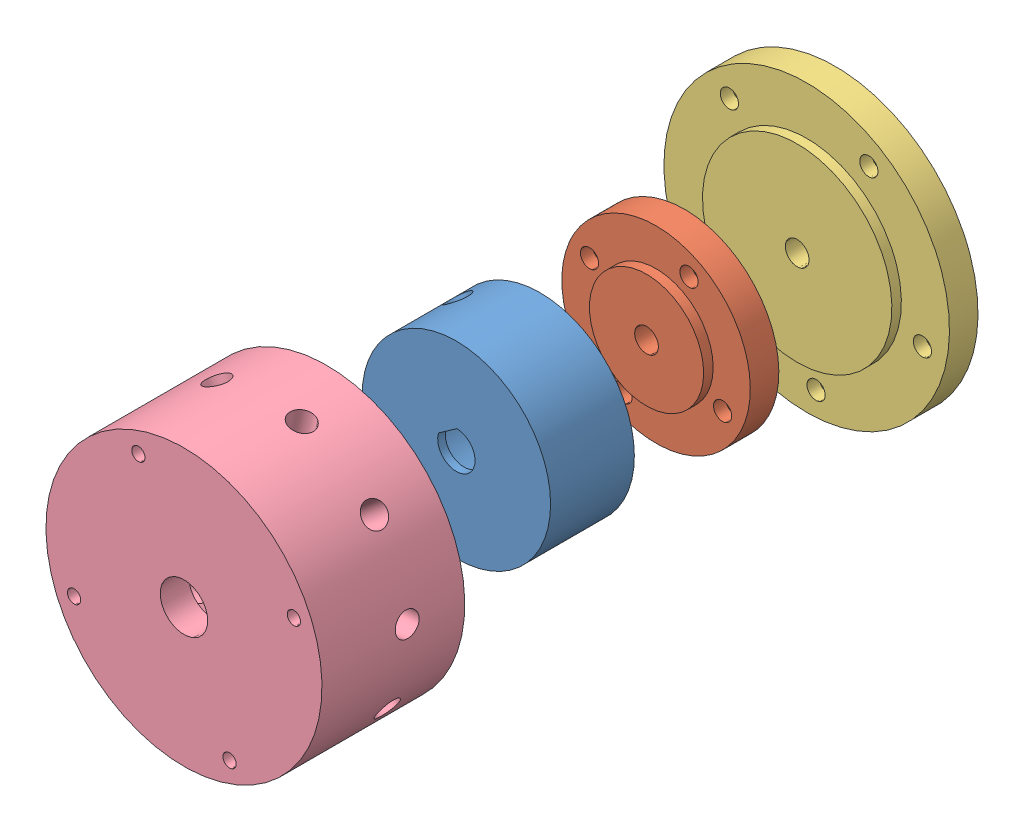
SolidWorks assembly Assem2, configuration Default. Lengths in mm.
Overall size (49.79 49.79 86.89).
4 component instances, 4 part files, 5 mates.
Components (placement in the parent):
- InnerBase-1: InnerBase [Default] at (-80.8877 -60.7818 -36.3421) x (-0.819375 -0.573257 0) z (0 0 -1) size (25.15 25.15 11.18)
- InnerCap-1: InnerCap [Default] at (-80.8877 -60.7818 -66.7947) x (-0.896212 0.443626 0) z (0 0 1) size (25.15 25.15 5.08)
- OuterCap-1: OuterCap [Default] at (-80.8877 -60.7818 -86.8932) x (0.923728 0.383049 0) z (0 0 1) size (38.1 38.1 5.08)
- OuterRing-1: OuterRing [Default] at (-80.8877 -60.7818 0) x (-0.923728 -0.383049 0) z (0 0 -1) size (36.83 36.83 19.05)
Mates (geometry in assembly coordinates):
- Concentric1: concentric anti-aligned: cylinder of OuterCap-1 through (-80.8877 -60.7818 -83.0832) axis (0 0 -1) radius 19.05; cylinder of OuterRing-1 through (-80.8877 -60.7818 -19.05) axis (0 0 1) radius 18.415
- Coincident1: coincident aligned: plane of OuterRing-1 through (-80.8877 -60.7818 0) normal (0 0 1); plane of assembly through (0 0 0) normal (0 0 1)
- Concentric2: concentric anti-aligned: cylinder of InnerBase-1 through (-80.8877 -60.7818 -47.5181) axis (0 0 1) radius 12.573; cylinder of InnerCap-1 through (-80.8877 -60.7818 -62.9847) axis (0 0 -1) radius 12.573
- Concentric3: concentric aligned: cylinder of InnerBase-1 through (-80.8877 -60.7818 -47.5181) axis (0 0 1) radius 12.573; cylinder of OuterRing-1 through (-80.8877 -60.7818 -19.05) axis (0 0 1) radius 18.415
- Concentric4: concentric aligned: circle of OuterCap-1; circle of OuterRing-1
